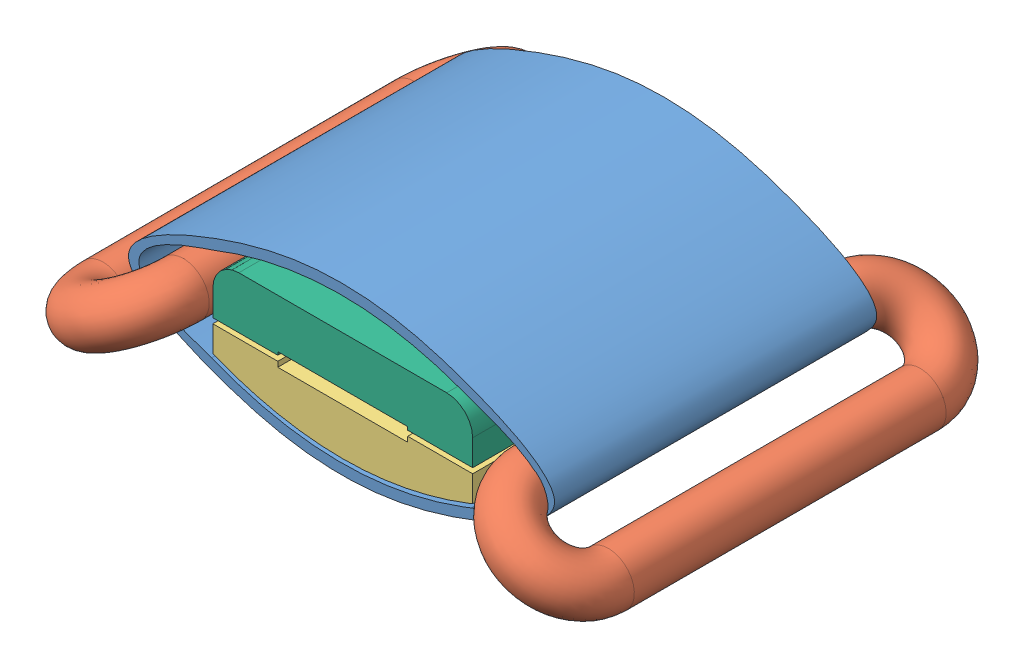
SolidWorks assembly Felxiforce case with hoop, configuration Default. Lengths in mm.
Overall size (54.93 16.44 44.35).
7 component instances, 6 part files, 13 mates.
Components (placement in the parent):
- Sensor compressive case with bottom-1: Sensor compressive case with bottom [Default] at (3.6916 13.6143 20.2212) size (41 16 31)
- Flexiforce hoop-1: Flexiforce hoop [Default] at (-3.5191 17.8388 50.5935) x (-0.001927 0.000668 -0.999998) z (0.880639 0.473787 -0.001381) size (43.75 5 13.75)
- Flexiforce hoop-2: Flexiforce hoop [Default] at (36.9472 17.9522 50.0026) x (0 0 -1) z (0.845875 -0.533381 0) size (43.75 5 13.75)
- Sensor holder part 1-1: Sensor holder part 1 [Default] at (3.812 16.5205 51.2212) size (25 5 30)
- button top-2: button top [Default] at (3.8121 25.0205 25.2279) x (1 0 0) z (0 -1 0) size (20.21 20 2.59)
- Button-2: Button [Default] at (16.312 20.0205 35.2212) x (0.999978 0 -0.006697) z (-0.006697 0 -0.999978) size (8 9 8)
- Sensor holder upper l-2: Sensor holder upper l [Default] at (28.812 24.5205 51.2212) x (-1 0 0) z (0 0 1) size (25 7.5 30)
Mates (geometry in assembly coordinates):
- Tangent1: tangent: cylinder of assembly; face of Sensor compressive case with bottom-1; cylinder of Flexiforce hoop-1 through (0.3337 19.9117 50.5875) axis (-0.001927 0.000668 -0.999998) radius 2.5
- Parallel6: parallel: cylinder of assembly; face of Sensor compressive case with bottom-1; cylinder of Flexiforce hoop-2 through (33.2465 20.2858 20.0026) axis (0 0 1) radius 2.5
- Tangent6: tangent: cylinder of assembly; face of Sensor compressive case with bottom-1; cylinder of Flexiforce hoop-2 through (33.2465 20.2858 20.0026) axis (0 0 1) radius 2.5
- Concentric1: concentric aligned: cylinder of Button-2 through (16.312 25.0205 35.2212) axis (0 -1 0) radius 2; cylinder of Sensor holder upper l-2 through (16.312 29.5205 35.2212) axis (0 -1 0) radius 2.6
- Distance1: distance = 1 mm anti-aligned: plane of Button-2 through (16.312 20.0205 35.2212) normal (0 1 0); plane of Sensor holder upper l-2 through (16.312 21.0205 35.2212) normal (0 -1 0)
- Concentric2: concentric aligned: cylinder of button top-2 through (16.3121 45.0205 35.2279) axis (0 -1 0) radius 1.55; cylinder of Button-2 through (16.3121 27.5205 35.2279) axis (0 -1 0) radius 1.5
- Coincident2: coincident anti-aligned: plane of button top-2 through (3.8121 25.0205 45.2279) normal (0 -1 0); plane of Button-2 through (16.312 25.0205 35.2212) normal (0 1 0)
- Parallel7: parallel aligned: plane of button top-2 through (3.8121 25.0205 25.2279) normal (0 0 -1); plane of Sensor holder upper l-2 through (28.812 19.5205 21.2212) normal (0 0 -1)
- Concentric3: concentric aligned: cylinder of Sensor holder part 1-1 through (24.812 15.5205 24.2212) axis (0 1 0) radius 2; cylinder of Sensor holder upper l-2 through (24.812 17.0205 24.2212) axis (0 1 0) radius 1.85
- Concentric4: concentric aligned: cylinder of Sensor holder part 1-1 through (7.812 15.5205 24.2212) axis (0 1 0) radius 2; cylinder of Sensor holder upper l-2 through (7.812 17.0205 24.2212) axis (0 1 0) radius 1.85
- Distance2: distance = 0.5 mm anti-aligned: plane of Sensor holder upper l-2 through (28.812 19.5205 51.2212) normal (0 -1 0); plane of Sensor holder part 1-1 through (3.812 19.0205 51.2212) normal (0 1 0)
- Coincident5: coincident anti-aligned: plane of Sensor compressive case with bottom-1 through (3.6916 13.6143 21.2212) normal (0 0 1); plane of Sensor holder upper l-2 through (28.812 19.5205 21.2212) normal (0 0 -1)
- Parallel8: parallel: face of Sensor compressive case with bottom-1; face of Sensor holder part 1-1
